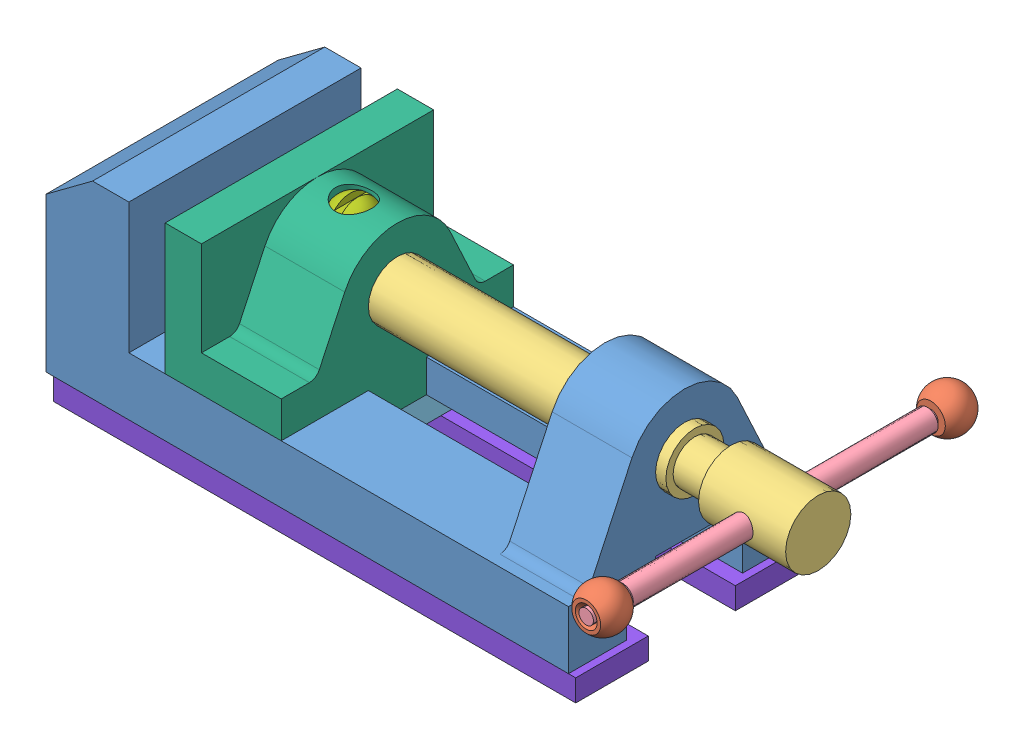
SolidWorks assembly Assem1, configuration Default. Lengths in mm.
Overall size (180.84 58.6 104).
12 component instances, 9 part files, 27 mates.
Components (placement in the parent):
- Part1-1: Part1 [Default] at (-25.1312 51.5046 112.5624) size (144 52 64)
- Part10-1: Part10 [Default] at (143.7083 87.5046 160.013) x (0.980437 -0.196831 0) z (-0.196831 -0.980437 0) size (12 9 12)
- Part4-1: Part4 [Default] at (17.7083 87.5046 112.5624) x (0 1 0) z (0 0 -1) size (18 138 18)
- Part6-1: Part6 [Default] at (143.7083 87.5046 164.513) x (0.995812 0.091426 0) z (-0.091426 0.995812 0) size (6 104 6)
- Part5-1: Part5 [Default] at (23.7083 58.5046 112.5624) x (-1 0 0) z (0 0 1) size (32 7 32)
- Part2-1: Part2 [Default] at (17.7083 67.5046 144.5624) x (0 0 -1) z (1 0 0) size (64 45 32)
- Part9-1: Part9 [Default] at (27.7083 91.5046 112.5624) size (10 12.6 14)
- Part10-2: Part10 [Default] at (143.7083 87.5046 65.013) x (-0.975401 -0.22044 0) z (0.22044 -0.975401 0) size (12 9 12)
- Part3-1: Part3 [Default] at (120.8688 51.5046 100.5624) x (-1 0 0) z (0 0 1) size (144 6 20)
- Part3-2: Part3 [Default] at (120.8688 51.5046 144.5624) x (-1 0 0) z (0 0 1) size (144 6 20)
- Part8-1: Part8 [Default] at (15.7083 74.1311 112.5624) x (0.734964 0 -0.678107) z (-0.678107 0 -0.734964) size (13 22.63 12.85)
- Part8-2: Part8 [Default] at (31.7083 74.1311 112.5624) x (0.265757 0 0.96404) z (0.96404 0 -0.265757) size (13 22.63 12.85)
Mates (geometry in assembly coordinates):
- Coincident1: coincident anti-aligned: plane of Part1-1 through (-2.2917 67.5046 144.5624) normal (0 1 0); plane of Part2-1 through (39.7083 67.5046 144.5624) normal (0 -1 0)
- Coincident2: coincident anti-aligned: plane of Part1-1 through (-25.1322 67.5046 104.5624) normal (0 0 1); plane of Part2-1 through (39.7083 67.5046 104.5624) normal (0 0 -1)
- Distance1: distance = 10 mm anti-aligned: plane of Part1-1 through (-2.2917 103.5046 144.5624) normal (1 0 0); plane of Part2-1 through (7.7083 67.5046 144.5624) normal (-1 0 0)
- Concentric2: concentric aligned: cylinder of Part4-1 through (155.7083 87.5046 112.5624) axis (1 0 0) radius 6; cylinder of Part2-1 through (15.7083 87.5046 112.5624) axis (1 0 0) radius 6
- Coincident4: coincident anti-aligned: plane of Part4-1 through (39.7083 93.5046 112.5624) normal (-1 0 0); plane of Part2-1 through (39.7083 67.5046 144.5624) normal (1 0 0)
- Coincident9: coincident aligned: plane of Part2-1 through (27.7083 99.5046 109.5624) normal (0 1 0); circle of Part9-1
- Concentric3: concentric aligned: cylinder of Part2-1 through (27.7083 103.5046 112.5624) axis (0 1 0) radius 3; cylinder of Part9-1 through (27.7083 101.5046 112.5624) axis (0 1 0) radius 3
- Concentric4: concentric aligned: cylinder of Part4-1 through (143.7083 87.5046 121.5624) axis (0 0 -1) radius 3; cylinder of Part6-1 through (143.7083 87.5046 60.513) axis (0 0 -1) radius 3
- Coincident14: coincident anti-aligned: plane of Part4-1 through (17.7083 87.5046 112.5624) normal (0 0 -1); plane of Part5-1 through (23.7083 58.5046 112.5624) normal (0 0 1)
- Concentric5: concentric anti-aligned: cylinder of Part10-1 through (143.7083 87.5046 165.5475) axis (0 0 1) radius 2; cylinder of Part6-1 through (143.7083 87.5046 60.513) axis (0 0 -1) radius 2
- Coincident15: coincident aligned: plane of Part10-1 through (145.6692 87.111 164.513) normal (0 0 1); plane of Part6-1 through (143.7083 87.5046 164.513) normal (0 0 1)
- Concentric7: concentric aligned: cylinder of Part6-1 through (143.7083 87.5046 60.513) axis (0 0 -1) radius 2; cylinder of Part10-2 through (143.7083 87.5046 59.4785) axis (0 0 -1) radius 2
- Coincident17: coincident aligned: plane of Part6-1 through (145.6999 87.6875 60.513) normal (0 0 -1); plane of Part10-2 through (141.7575 87.0638 60.513) normal (0 0 -1)
- Coincident19: coincident anti-aligned: plane of Part1-1 through (118.8688 51.5046 144.5624) normal (0 -1 0); plane of Part3-1 through (120.8688 51.5046 100.5624) normal (0 1 0)
- Concentric9: concentric aligned: cylinder of Part1-1 through (82.8688 61.5046 90.5624) axis (0 -1 0) radius 3; cylinder of Part3-1 through (82.8688 45.5046 90.5624) axis (0 -1 0) radius 3
- Concentric10: concentric aligned: cylinder of Part1-1 through (12.8688 61.5046 90.5624) axis (0 -1 0) radius 3; cylinder of Part3-1 through (12.8688 45.5046 90.5624) axis (0 -1 0) radius 3
- Coincident20: coincident anti-aligned: plane of Part1-1 through (118.8688 51.5046 144.5624) normal (0 -1 0); plane of Part3-2 through (120.8688 51.5046 144.5624) normal (0 1 0)
- Concentric11: concentric aligned: cylinder of Part1-1 through (12.8688 61.5046 134.5624) axis (0 -1 0) radius 3; cylinder of Part3-2 through (12.8688 45.5046 134.5624) axis (0 -1 0) radius 3
- Concentric12: concentric aligned: cylinder of Part1-1 through (82.8688 61.5046 134.5624) axis (0 -1 0) radius 3; cylinder of Part3-2 through (82.8688 45.5046 134.5624) axis (0 -1 0) radius 3
- Coincident21: coincident anti-aligned: plane of Part5-1 through (23.7083 58.5046 112.5624) normal (0 1 0); plane of Part2-1 through (39.7083 58.5046 144.5624) normal (0 -1 0)
- Concentric15: concentric aligned: cylinder of Part5-1 through (15.7083 51.5046 112.5624) axis (0 -1 0) radius 3.5; cylinder of Part2-1 through (15.7083 74.5046 112.5624) axis (0 -1 0) radius 3
- Coincident22: coincident aligned: plane of Part5-1 through (39.7083 51.5046 128.5624) normal (1 0 0); plane of Part2-1 through (39.7083 67.5046 144.5624) normal (1 0 0)
- Coincident23: coincident anti-aligned: plane of Part4-1 through (17.7083 87.5046 112.5624) normal (0 0 -1); plane of Part5-1 through (23.7083 58.5046 112.5624) normal (0 0 1)
- Concentric25: concentric aligned: cylinder of Part2-1 through (15.7083 74.5046 112.5624) axis (0 -1 0) radius 3; cylinder of Part8-1 through (15.7083 51.5046 112.5624) axis (0 -1 0) radius 2.5981
- Coincident25: coincident aligned: plane of Part5-1 through (23.7083 51.5046 112.5624) normal (0 -1 0); plane of Part8-1 through (20.4856 51.5046 108.1548) normal (0 -1 0)
- Concentric28: concentric aligned: cylinder of Part2-1 through (31.7083 74.5046 112.5624) axis (0 -1 0) radius 3; cylinder of Part8-2 through (31.7083 51.5046 112.5624) axis (0 -1 0) radius 2.5981
- Coincident26: coincident aligned: plane of Part5-1 through (23.7083 51.5046 112.5624) normal (0 -1 0); plane of Part8-2 through (33.4357 51.5046 118.8287) normal (0 -1 0)
